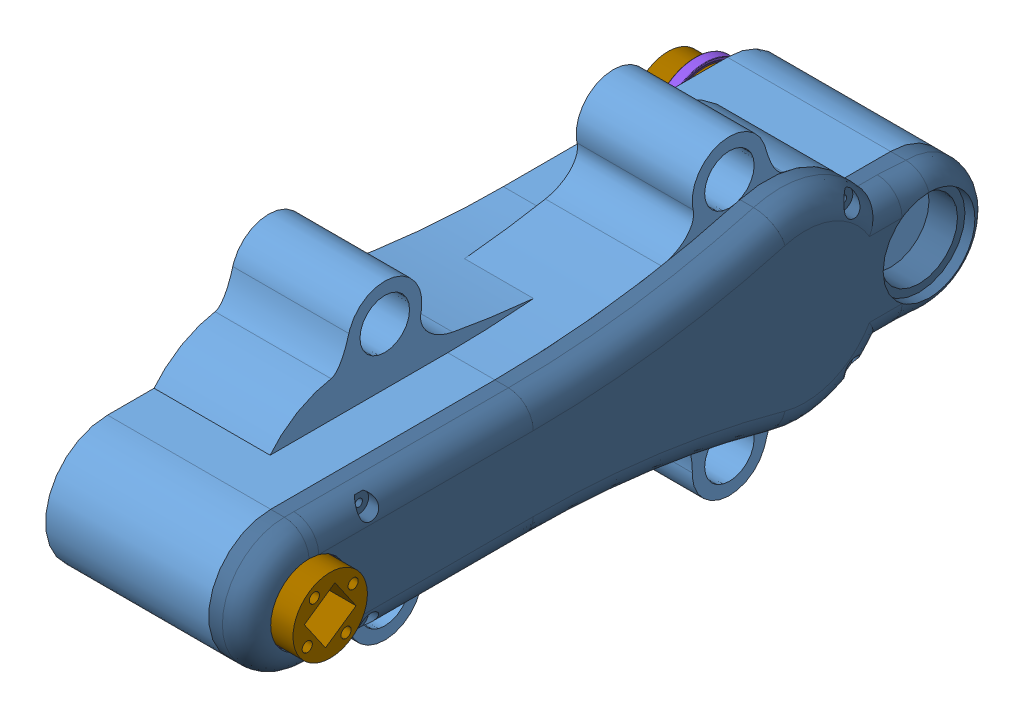
SolidWorks assembly middle hip assembly, configuration Default. Lengths in mm.
Overall size (113.8 125.46 312.7).
24 component instances, 10 part files, 52 mates.
Components (placement in the parent):
- middlehip-1: middlehip [Default] at (11.3116 104.098 379.5381) x (0 0 1) z (0 1 0) size (300 65.95 125.46)
- MAD5008IPE-1: MAD5008IPE [Default] at (159.7677 321.136 373.9919) x (0 -1 0) z (0 0 1) size (56 29.3 56)
- GT2 15 Teeth motor-1: GT2 15 Teeth motor [Default] at (187.1831 321.136 373.9919) x (0 -0.983291 -0.182042) z (0 -0.182042 0.983291) size (24 30 24)
- encoder holder-1: encoder holder [Default] at (195.5677 321.136 373.9919) x (0 -1 0) z (0 0 1) size (70 5 40.98)
- encoder-1: encoder [Default] at (204.3377 321.136 373.9919) x (0 -0.999698 0.024586) z (1 0 0) size (28.79 43.54 9.21)
- W_617_8-1: W_617_8 [Default] at (213.0677 321.136 373.9919) x (1 0 0) z (0 0.222195 -0.975002) size (2.5 14.75 14.75)
- 15_45 pulley-1: 15_45 pulley [Default] at (212.6391 322.7488 472.5197) x (0 0.827218 0.561881) z (0 -0.561881 0.827218) size (34 30.5 34)
- W_617_8-2: W_617_8 [Default] at (185.5677 321.136 483.5919) x (-1 0 0) z (0 -0.688036 0.725676) size (2.5 14.75 14.75)
- W_617_8-3: W_617_8 [Default] at (213.5677 321.136 483.5919) x (-1 0 0) z (0 0.985966 0.166946) size (2.5 14.75 14.75)
- W_61706_2RZ-1: W_61706_2RZ [Default] at (183.0677 321.136 573.9919) x (1 0 0) z (0 0.924225 0.381849) size (4 46.12 46.12)
- knee joint 45T-1: knee joint 45T [Default] at (196.5677 321.136 573.9919) x (0 -0.822956 -0.568105) z (0 -0.568105 0.822956) size (34 41.5 34)
- W_61706_2RZ-2: W_61706_2RZ [Default] at (213.5677 321.136 573.9919) x (-1 0 0) z (0 0.924225 0.381849) size (4 46.12 46.12)
- hip joint cover-1: hip joint cover [Default] at (211.0677 321.136 373.9919) x (0 0 1) z (0 -1 0) size (300 15.92 80)
- MAD5008IPE-2: MAD5008IPE [Default] at (175.5677 321.136 523.9919) x (0 -1 0) z (0 0 -1) size (56 29.3 56)
- encoder holder-2: encoder holder [Default] at (139.7677 321.136 523.9919) x (0 -1 0) z (0 0 -1) size (70 5 40.98)
- GT2 15 Teeth motor-2: GT2 15 Teeth motor [Default] at (148.1523 321.136 523.9919) x (0 0.983291 -0.182042) z (0 0.182042 0.983291) size (24 30 24)
- encoder-2: encoder [Default] at (130.9977 321.136 523.9919) x (0 -0.99808 -0.061937) z (-1 0 0) size (28.79 43.54 9.21)
- W_617_8-4: W_617_8 [Default] at (119.7677 321.136 523.9919) x (1 0 0) z (0 -0.933414 0.358801) size (2.5 14.75 14.75)
- W_617_8-5: W_617_8 [Default] at (149.7677 321.136 414.3919) x (1 0 0) z (0 -0.933414 0.358801) size (2.5 14.75 14.75)
- 15_45 pulley-2: 15_45 pulley [Default] at (122.6964 319.5231 403.3197) x (0 -0.827218 0.561881) z (0 0.561881 0.827218) size (34 30.5 34)
- W_61706_2RZ-3: W_61706_2RZ [Default] at (148.2677 321.136 323.9919) size (4 46.12 46.12)
- knee joint 45T-2: knee joint 45T [Default] at (138.7677 321.136 323.9919) x (0 0.822956 -0.568105) z (0 0.568105 0.822956) size (34 41.5 34)
- W_61706_2RZ-4: W_61706_2RZ [Default] at (121.7677 321.136 323.9919) x (1 0 0) z (0 0.738221 0.674559) size (4 46.12 46.12)
- hip joint cover-2: hip joint cover [Default] at (124.2677 321.136 523.9919) x (0 0 -1) z (0 -1 0) size (300 15.92 80) (hidden)
Mates (geometry in assembly coordinates):
- Concentric1: concentric: cylinder of middlehip-1 through (200.5677 321.136 373.9919) axis (-1 0 0) radius 30; cylinder of MAD5008IPE-1 through (185.5677 321.136 373.9919) axis (-1 0 0) radius 28
- Concentric2: concentric: cylinder of middlehip-1 through (200.5677 321.136 358.9919) axis (-1 0 0) radius 1.5; cylinder of MAD5008IPE-1 through (162.7677 321.136 358.9919) axis (-1 0 0) radius 1.5
- Coincident1: coincident: plane of middlehip-1 through (159.7677 321.136 373.9919) normal (1 0 0); plane of MAD5008IPE-1 through (159.7677 321.136 373.9919) normal (-1 0 0)
- Concentric3: concentric: cylinder of middlehip-1 through (200.5677 321.136 373.9919) axis (-1 0 0) radius 30; cylinder of GT2 15 Teeth motor-1 through (187.1831 321.136 373.9919) axis (-1 0 0) radius 12
- Coincident2: coincident: plane of MAD5008IPE-1 through (185.5677 321.136 373.9919) normal (1 0 0); plane of GT2 15 Teeth motor-1 through (185.5677 332.9354 376.1764) normal (-1 0 0)
- Coincident3: coincident: plane of middlehip-1 through (195.5677 353.2788 383.575) normal (0 -0.958315 -0.285714); plane of encoder holder-1 through (200.5677 353.2788 383.575) normal (0 0.958315 0.285714)
- Coincident4: coincident: plane of middlehip-1 through (195.5677 321.136 373.9919) normal (0 0.285714 -0.958315); plane of encoder holder-1 through (200.5677 321.136 373.9919) normal (0 -0.285714 0.958315)
- Coincident5: coincident: plane of middlehip-1 through (195.5677 321.136 373.9919) normal (1 0 0); plane of encoder holder-1 through (195.5677 321.136 373.9919) normal (-1 0 0)
- Coincident6: coincident: plane of encoder holder-1 through (200.5677 321.136 373.9919) normal (1 0 0); plane of encoder-1 through (200.5677 336.2085 401.677) normal (-1 0 0)
- Concentric4: concentric: cylinder of GT2 15 Teeth motor-1 through (187.254 321.136 373.9919) axis (1 0 0) radius 4; cylinder of encoder-1 through (204.6909 321.136 373.9919) axis (1 0 0) radius 2
- Coincident7: coincident: plane of GT2 15 Teeth motor-1 through (215.5677 321.136 373.9919) normal (1 0 0); plane of W_617_8-1 through (215.5677 317.0897 373.0697) normal (1 0 0)
- Concentric6: concentric: cylinder of GT2 15 Teeth motor-1 through (187.254 321.136 373.9919) axis (1 0 0) radius 4; cylinder of W_617_8-1 through (263.0677 321.136 373.9919) axis (1 0 0) radius 4
- Coincident8: coincident: plane of middlehip-1 through (183.0677 321.136 483.5919) normal (1 0 0); plane of W_617_8-2 through (183.0677 317.1447 479.8077) normal (-1 0 0)
- Concentric8: concentric: cylinder of middlehip-1 through (180.5677 321.136 483.5919) axis (1 0 0) radius 6; cylinder of W_617_8-2 through (135.5677 321.136 483.5919) axis (-1 0 0) radius 4
- Concentric9: concentric: cylinder of 15_45 pulley-1 through (183.0677 321.136 483.5919) axis (1 0 0) radius 4; cylinder of W_617_8-2 through (135.5677 321.136 483.5919) axis (-1 0 0) radius 4
- Coincident9: coincident: plane of 15_45 pulley-1 through (185.5677 321.136 483.5919) normal (-1 0 0); plane of W_617_8-2 through (185.5677 317.874 480.4991) normal (1 0 0)
- Coincident10: coincident: plane of 15_45 pulley-1 through (211.0677 321.136 483.5919) normal (1 0 0); plane of W_617_8-3 through (211.0677 320.4431 487.6836) normal (-1 0 0)
- Concentric11: concentric: cylinder of 15_45 pulley-1 through (213.5677 321.136 483.5919) axis (-1 0 0) radius 4; cylinder of W_617_8-3 through (163.5677 321.136 483.5919) axis (-1 0 0) radius 4
- Concentric12: concentric: cylinder of middlehip-1 through (180.5677 321.136 573.9919) axis (1 0 0) radius 18.5; cylinder of W_61706_2RZ-1 through (233.0677 321.136 573.9919) axis (1 0 0) radius 15
- Coincident12: coincident: plane of middlehip-1 through (183.0677 321.136 573.9919) normal (1 0 0); plane of W_61706_2RZ-1 through (183.0677 327.2965 559.081) normal (-1 0 0)
- Concentric13: concentric: cylinder of W_61706_2RZ-1 through (233.0677 321.136 573.9919) axis (1 0 0) radius 15; cylinder of knee joint 45T-1 through (183.0677 321.136 573.9919) axis (1 0 0) radius 15
- Coincident13: coincident: plane of W_61706_2RZ-1 through (187.0677 326.9401 559.9436) normal (1 0 0); plane of knee joint 45T-1 through (187.0677 321.136 573.9919) normal (-1 0 0)
- Concentric14: concentric: cylinder of knee joint 45T-1 through (224.5677 321.136 573.9919) axis (-1 0 0) radius 15; cylinder of W_61706_2RZ-2 through (163.5677 321.136 573.9919) axis (-1 0 0) radius 15
- Coincident14: coincident: plane of knee joint 45T-1 through (209.5677 321.136 573.9919) normal (1 0 0); plane of W_61706_2RZ-2 through (209.5677 315.3318 588.0401) normal (-1 0 0)
- Concentric15: concentric: cylinder of middlehip-1 through (200.5677 321.136 373.9919) axis (-1 0 0) radius 40; cylinder of hip joint cover-1 through (200.5677 321.136 373.9919) axis (1 0 0) radius 40
- Concentric16: concentric: cylinder of middlehip-1 through (200.5677 321.136 573.9919) axis (-1 0 0) radius 25; cylinder of hip joint cover-1 through (200.5677 321.136 573.9919) axis (1 0 0) radius 25
- Coincident15: coincident: plane of middlehip-1 through (200.5677 321.136 373.9919) normal (1 0 0); plane of hip joint cover-1 through (200.5677 321.136 373.9919) normal (-1 0 0)
- Concentric17: concentric: cylinder of middlehip-1 through (134.7677 321.136 523.9919) axis (1 0 0) radius 30; cylinder of MAD5008IPE-2 through (149.7677 321.136 523.9919) axis (1 0 0) radius 28
- Concentric18: concentric: cylinder of middlehip-1 through (134.7677 336.136 523.9919) axis (1 0 0) radius 1.5; cylinder of MAD5008IPE-2 through (172.5677 336.136 523.9919) axis (1 0 0) radius 1.5
- Coincident16: coincident: plane of middlehip-1 through (175.5677 321.136 523.9919) normal (-1 0 0); plane of MAD5008IPE-2 through (175.5677 321.136 523.9919) normal (1 0 0)
- Concentric19: concentric: cylinder of MAD5008IPE-2 through (146.2677 321.136 523.9919) axis (1 0 0) radius 2; cylinder of GT2 15 Teeth motor-2 through (148.1523 321.136 523.9919) axis (1 0 0) radius 12
- Coincident17: coincident: plane of MAD5008IPE-2 through (149.7677 321.136 523.9919) normal (-1 0 0); plane of GT2 15 Teeth motor-2 through (149.7677 309.3365 526.1764) normal (1 0 0)
- Coincident18: coincident: plane of middlehip-1 through (139.7677 353.2788 514.4087) normal (0 -0.958315 0.285714); plane of encoder holder-2 through (134.7677 353.2788 514.4087) normal (0 0.958315 -0.285714)
- Coincident19: coincident: plane of middlehip-1 through (139.7677 321.136 523.9919) normal (0 0 -1); plane of encoder holder-2 through (134.7677 321.136 523.9919) normal (0 0 1)
- Coincident20: coincident: plane of middlehip-1 through (139.7677 321.136 523.9919) normal (-1 0 0); plane of encoder holder-2 through (139.7677 321.136 523.9919) normal (1 0 0)
- Concentric20: concentric: cylinder of GT2 15 Teeth motor-2 through (148.0814 321.136 523.9919) axis (-1 0 0) radius 4; cylinder of encoder-2 through (130.6445 321.136 523.9919) axis (-1 0 0) radius 2
- Coincident21: coincident: plane of encoder holder-2 through (134.7677 321.136 523.9919) normal (-1 0 0); plane of encoder-2 through (134.7677 337.2328 496.8895) normal (1 0 0)
- Concentric21: concentric: cylinder of middlehip-1 through (154.7677 321.136 414.3919) axis (-1 0 0) radius 6; cylinder of W_617_8-5 through (199.7677 321.136 414.3919) axis (1 0 0) radius 4
- Coincident22: coincident: plane of middlehip-1 through (152.2677 321.136 414.3919) normal (-1 0 0); plane of W_617_8-5 through (152.2677 322.625 418.2655) normal (1 0 0)
- Coincident23: coincident: plane of GT2 15 Teeth motor-2 through (119.7677 321.136 523.9919) normal (-1 0 0); plane of W_617_8-4 through (119.7677 322.7488 528.1876) normal (-1 0 0)
- Concentric22: concentric: cylinder of GT2 15 Teeth motor-2 through (148.0814 321.136 523.9919) axis (-1 0 0) radius 4; cylinder of W_617_8-4 through (169.7677 321.136 523.9919) axis (1 0 0) radius 4
- Concentric23: concentric: cylinder of W_617_8-5 through (199.7677 321.136 414.3919) axis (1 0 0) radius 4; cylinder of 15_45 pulley-2 through (152.2677 321.136 414.3919) axis (-1 0 0) radius 4
- Coincident24: coincident: plane of W_617_8-5 through (149.7677 322.7488 418.5876) normal (-1 0 0); plane of 15_45 pulley-2 through (149.7677 321.136 414.3919) normal (1 0 0)
- Concentric24: concentric: cylinder of middlehip-1 through (154.7677 321.136 323.9919) axis (-1 0 0) radius 18.5; cylinder of W_61706_2RZ-3 through (198.2677 321.136 323.9919) axis (1 0 0) radius 15
- Coincident25: coincident: plane of middlehip-1 through (152.2677 321.136 323.9919) normal (-1 0 0); plane of W_61706_2RZ-3 through (152.2677 336.336 323.9919) normal (1 0 0)
- Concentric25: concentric: cylinder of knee joint 45T-2 through (152.2677 321.136 323.9919) axis (-1 0 0) radius 15; cylinder of W_61706_2RZ-3 through (198.2677 321.136 323.9919) axis (1 0 0) radius 15
- Coincident26: coincident: plane of W_61706_2RZ-3 through (148.2677 337.2693 323.9919) normal (-1 0 0); plane of knee joint 45T-2 through (148.2677 321.136 323.9919) normal (1 0 0)
- Concentric26: concentric: cylinder of W_61706_2RZ-4 through (171.7677 321.136 323.9919) axis (1 0 0) radius 15; cylinder of knee joint 45T-2 through (110.7677 321.136 323.9919) axis (1 0 0) radius 15
- Coincident27: coincident: plane of knee joint 45T-2 through (125.7677 321.136 323.9919) normal (-1 0 0); plane of W_61706_2RZ-4 through (125.7677 331.3892 312.7709) normal (1 0 0)
- Concentric27: concentric: cylinder of middlehip-1 through (181.5677 321.136 523.9919) axis (-1 0 0) radius 40; cylinder of hip joint cover-2 through (134.7677 321.136 523.9919) axis (-1 0 0) radius 40
- Concentric28: concentric: cylinder of middlehip-1 through (134.7677 321.136 323.9919) axis (1 0 0) radius 25; cylinder of hip joint cover-2 through (134.7677 321.136 323.9919) axis (-1 0 0) radius 25
- Coincident28: coincident: plane of middlehip-1 through (134.7677 321.136 523.9919) normal (-1 0 0); plane of hip joint cover-2 through (134.7677 321.136 523.9919) normal (1 0 0)
